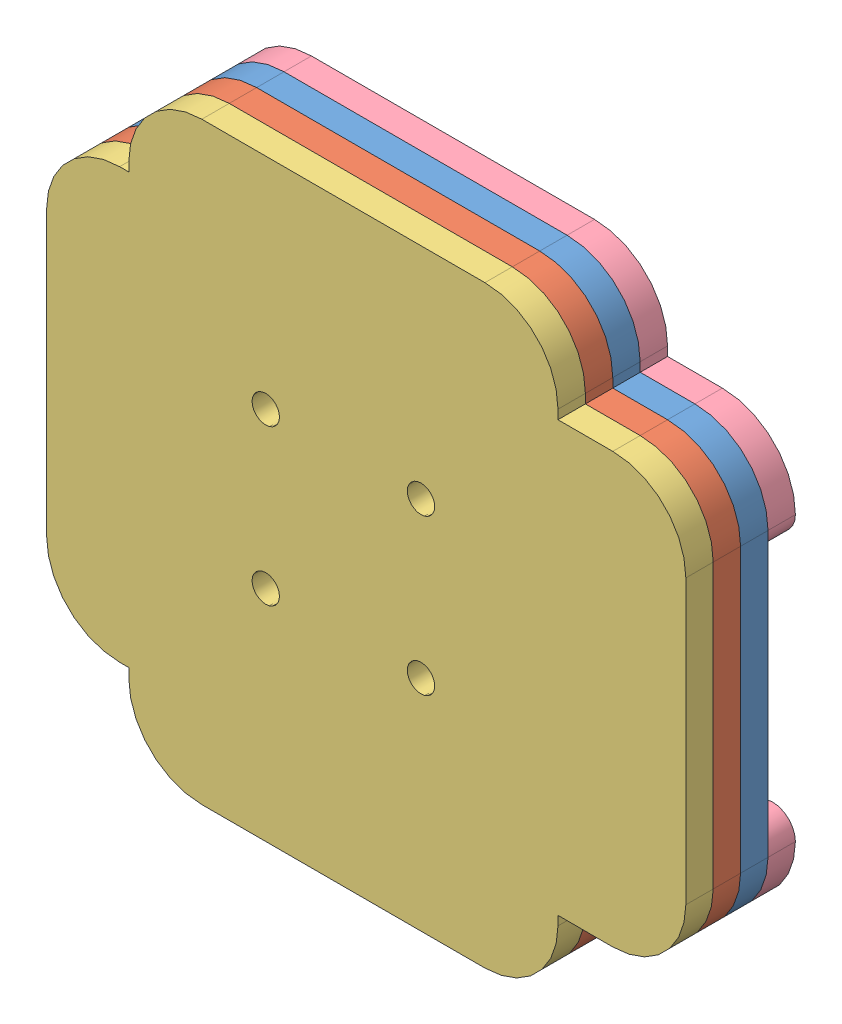
SolidWorks assembly Montagem3, configuration Valor predeterminado. Lengths in mm.
Overall size (70 65 12).
6 component instances, 6 part files, 18 mates.
Components (placement in the parent):
- Cópia de Peça4^Montagem3-1: Cópia de Peça4^Montagem3 [Valor predeterminado] at (-116.4614 -15.9543 -5) size (60 55 10) (hidden, virtual)
- Braçadeira1-1: Braçadeira1 [Valor predeterminado] at (-116.4614 -15.9543 18.4293) size (70 65 3)
- Base_sensor^Montagem3-1: Base_sensor^Montagem3 [Valor predeterminado] at (-116.4614 -15.9543 21.4293) size (70 65 3) (virtual)
- Base-1: Base [Valor predeterminado] at (-116.4614 -15.9543 24.4293) size (70 65 3)
- BraçadeiraFios-1: BraçadeiraFios [Valor predeterminado] at (-116.4614 -15.9543 18.4293) x (-1 0 0) z (0 0 -1) size (70 65 3)
- CentralizadorImã-1: CentralizadorImã [Valor predeterminado] at (-116.4614 -15.9543 24.4293) x (-1 0 0) z (0 0 -1) size (10 10 3)
Mates (geometry in assembly coordinates):
- No local2: in place: plane of ? through (-80.8079 -13.5109 29.4194) normal (0 0 1); plane of ? through (0 0 29.4194) normal (0 0 1); moOrthogonalPlaneRef_w of ? through (-80.8079 -13.5109 29.4194) normal (0 0 1); plane of ? through (0 0 29.4194) normal (0 1 0); plane of ? through (-80.8079 -13.5109 29.4194) normal (0 0 1); plane of ? through (0 0 29.4194) normal (1 0 0); plane of Braçadeira1-1 through (-77.9614 -17.4543 21.4293) normal (0 0 1); unknown of Base_sensor^Montagem3-1
- Coincidente4: coincident aligned: plane of ?; plane of ?
- Coincidente5: coincident aligned: moOrthogonalPlaneRef_w of Peça5^Montagem3-1 through (-116.4614 -15.9543 21.4293) normal (0 1 0); plane of Peça6^Montagem3-1 through (-116.4614 -15.9543 21.4293) normal (0 1 0)
- Coincidente6: coincident anti-aligned: moOrthogonalPlaneRef_w of Peça5^Montagem3-1 through (-116.4614 -15.9543 21.4293) normal (-1 0 0); plane of Peça6^Montagem3-1 through (-116.4614 -15.9543 21.4293) normal (1 0 0)
- Coincidente9: coincident anti-aligned: plane of Cópia de Peça4^Montagem3-1 through (-120.9614 -15.9543 5) normal (-1 0 0); plane of Peça5^Montagem3-1 through (-120.9614 22.5457 21.4293) normal (1 0 0)
- Coincidente10: coincident anti-aligned: plane of Cópia de Peça4^Montagem3-1 through (-116.4614 -20.4543 5) normal (0 -1 0); plane of Peça5^Montagem3-1 through (-108.9614 -20.4543 21.4293) normal (0 1 0)
- No local3: in place: plane of Base_sensor^Montagem3-1 through (-77.9614 -17.4543 24.4293) normal (0 0 1); plane of ? through (0 0 24.4293) normal (0 0 1); plane of Base_sensor^Montagem3-1 through (-77.9614 -17.4543 24.4293) normal (0 0 1); plane of ? through (0 0 24.4293) normal (0 1 0); plane of Base_sensor^Montagem3-1 through (-77.9614 -17.4543 24.4293) normal (0 0 1); plane of ? through (0 0 24.4293) normal (1 0 0); plane of Base_sensor^Montagem3-1 through (-77.9614 -17.4543 24.4293) normal (0 0 1); unknown of Base-1
- Coincidente11: coincident aligned: plane of ?; plane of ?
- Coincidente12: coincident aligned: moOrthogonalPlaneRef_w of Peça6^Montagem3-1 through (-116.4614 -15.9543 24.4293) normal (0 1 0); plane of Base-1 through (-116.4614 -15.9543 24.4293) normal (0 1 0)
- Coincidente13: coincident anti-aligned: moOrthogonalPlaneRef_w of Peça6^Montagem3-1 through (-116.4614 -15.9543 24.4293) normal (-1 0 0); plane of Base-1 through (-116.4614 -15.9543 24.4293) normal (1 0 0)
- No local4: in place: plane of Braçadeira1-1 through (-77.9614 -17.4543 18.4293) normal (0 0 -1); plane of ? through (0 0 18.4293) normal (0 0 -1); plane of Braçadeira1-1 through (-77.9614 -17.4543 18.4293) normal (0 0 -1); plane of ? through (0 0 18.4293) normal (0 1 0); plane of Braçadeira1-1 through (-77.9614 -17.4543 18.4293) normal (0 0 -1); plane of ? through (0 0 18.4293) normal (-1 0 0); plane of Braçadeira1-1 through (-77.9614 -17.4543 18.4293) normal (0 0 -1); unknown of BraçadeiraFios-1
- Coincidente14: coincident aligned: plane of ?; plane of ?
- Coincidente15: coincident aligned: moOrthogonalPlaneRef_w of Peça5^Montagem3-1 through (-116.4614 -15.9543 18.4293) normal (0 1 0); plane of Peça8^Montagem3-1 through (-116.4614 -15.9543 18.4293) normal (0 1 0)
- Coincidente16: coincident anti-aligned: moOrthogonalPlaneRef_w of Peça5^Montagem3-1 through (-116.4614 -15.9543 18.4293) normal (1 0 0); plane of Peça8^Montagem3-1 through (-116.4614 -15.9543 18.4293) normal (-1 0 0)
- No local5: in place: plane of Base-1 through (-108.9614 -17.4543 24.4293) normal (0 0 -1); plane of ? through (0 0 24.4293) normal (0 0 -1); plane of Base-1 through (-108.9614 -17.4543 24.4293) normal (0 0 -1); plane of ? through (0 0 24.4293) normal (0 1 0); plane of Base-1 through (-108.9614 -17.4543 24.4293) normal (0 0 -1); plane of ? through (0 0 24.4293) normal (-1 0 0); plane of Base-1 through (-108.9614 -17.4543 24.4293) normal (0 0 -1); unknown of CentralizadorImã-1
- Coincidente17: coincident aligned: plane of ?; plane of ?
- Coincidente18: coincident aligned: moOrthogonalPlaneRef_w of Base-1 through (-116.4614 -15.9543 24.4293) normal (0 1 0); plane of Peça9^Montagem3-1 through (-116.4614 -15.9543 24.4293) normal (0 1 0)
- Coincidente19: coincident anti-aligned: moOrthogonalPlaneRef_w of Base-1 through (-116.4614 -15.9543 24.4293) normal (1 0 0); plane of Peça9^Montagem3-1 through (-116.4614 -15.9543 24.4293) normal (-1 0 0)
